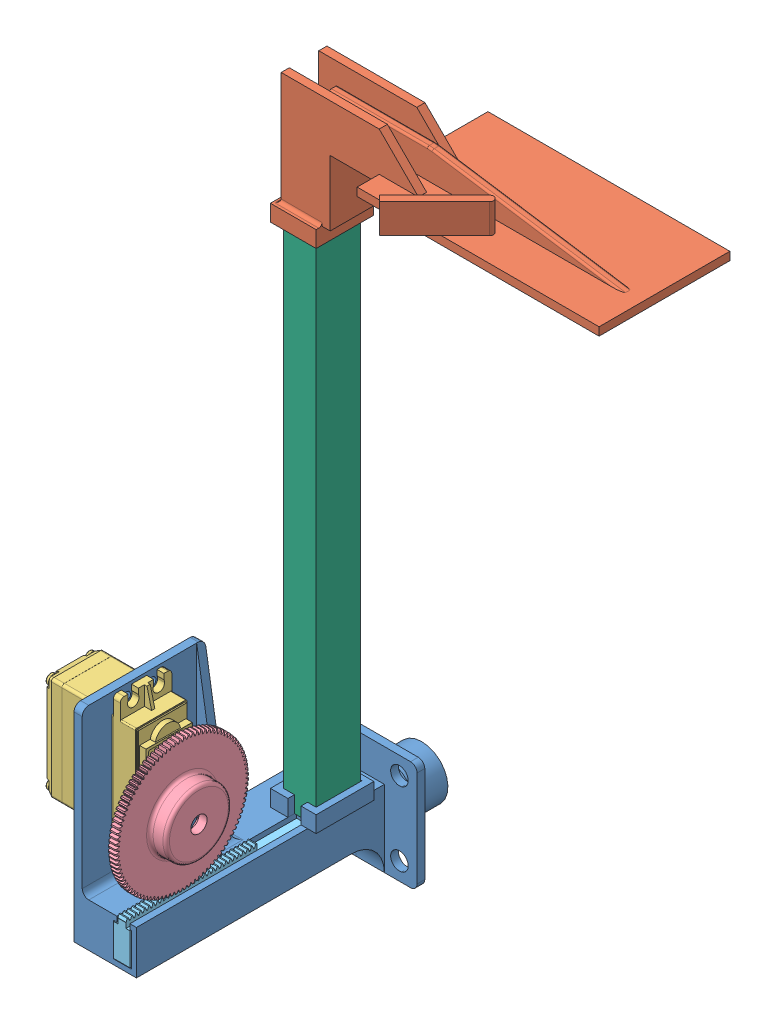
SolidWorks assembly FeederAssemV7, configuration Default. Lengths in mm.
Overall size (167.6 276.71 128.11).
6 component instances, 6 part files, 13 mates.
Components (placement in the parent):
- JawFeederV7-1: JawFeederV7 [Default] at (74.3523 66.8049 68.7901) size (36.94 92.64 116.3)
- RampSortV2-1: RampSortV2 [Default] at (108.9113 310.4049 122.9076) size (133.98 50.16 62.8)
- FeederServo-1: FeederServo [Default] at (73.4873 116.421 161.0061) x (0 1 0) z (1 0 0) size (54.3 20 43.9)
- DriveGear-1: DriveGear [2662N26] at (79.1874 106.571 161.0061) x (0 -0.383049 0.923728) z (-1 0 0) size (51.87 51.87 9.56)
- FeederPlungerV2-1: FeederPlungerV2 [2662N54] at (77.54 79.2509 132.1264) x (0 0 1) z (-1 0 0) size (88.9 15.62 6.35)
- Chimney3DPrint-1: Chimney3DPrint [Default] at (71.4463 81.8049 96.8091) x (0 0 1) z (-1 0 0) size (17.27 203.2 12.7)
Mates (geometry in assembly coordinates):
- Concentric1: concentric anti-aligned: circle of FeederServo-1; circle of DriveGear-1
- Distance1: distance = 3.175 mm anti-aligned: plane of DriveGear-1 through (82.3624 106.571 161.0061) normal (-1 0 0); plane of FeederServo-1 through (79.1873 106.571 161.0061) normal (1 0 0)
- Coincident8: coincident anti-aligned: plane of JawFeederV7-1 through (62.2873 66.8049 68.7901) normal (1 0 0); plane of FeederServo-1 through (62.2873 142.071 169.5061) normal (-1 0 0)
- Concentric2: concentric anti-aligned: circle of JawFeederV7-1; circle of FeederServo-1
- Concentric3: concentric aligned: circle of JawFeederV7-1; circle of FeederServo-1
- Coincident9: coincident anti-aligned: plane of JawFeederV7-1 through (74.3523 66.8049 144.9901) normal (1 0 0); plane of FeederPlungerV2-1 through (74.3523 79.2509 94.0264) normal (-1 0 0)
- Coincident10: coincident anti-aligned: plane of JawFeederV7-1 through (74.3523 66.8049 144.9901) normal (0 1 0); plane of FeederPlungerV2-1 through (74.3523 66.8049 94.0264) normal (0 -1 0)
- Coincident11: coincident anti-aligned: plane of JawFeederV7-1 through (74.3523 88.1549 114.0811) normal (0 0 -1); plane of Chimney3DPrint-1 through (71.4463 285.0049 114.0811) normal (0 0 1)
- Coincident12: coincident anti-aligned: plane of JawFeederV7-1 through (84.1463 88.1549 68.7901) normal (-1 0 0); plane of Chimney3DPrint-1 through (84.1463 285.0049 96.8091) normal (1 0 0)
- Coincident13: coincident anti-aligned: plane of JawFeederV7-1 through (72.3523 81.8049 144.9901) normal (0 1 0); plane of Chimney3DPrint-1 through (71.4463 81.8049 96.8091) normal (0 -1 0)
- Coincident14: coincident anti-aligned: plane of RampSortV2-1 through (71.4463 278.6549 114.0811) normal (0 0 -1); plane of Chimney3DPrint-1 through (71.4463 285.0049 114.0811) normal (0 0 1)
- Coincident15: coincident anti-aligned: plane of RampSortV2-1 through (84.1463 278.6549 114.0811) normal (-1 0 0); plane of Chimney3DPrint-1 through (84.1463 285.0049 96.8091) normal (1 0 0)
- Coincident16: coincident anti-aligned: plane of RampSortV2-1 through (108.9113 285.0049 122.9076) normal (0 -1 0); plane of Chimney3DPrint-1 through (71.4463 285.0049 96.8091) normal (0 1 0)
